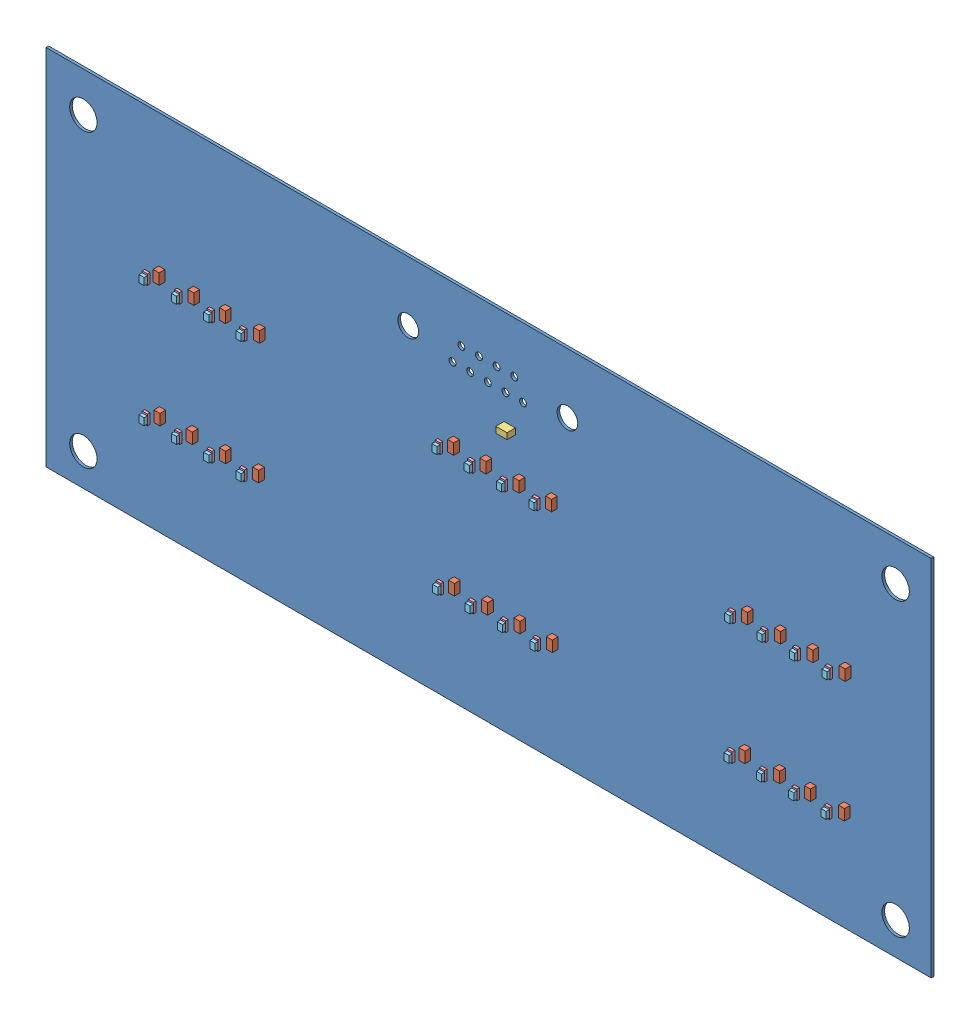
SolidWorks assembly FEV-60_LED_Panel, configuration Default. Lengths in mm.
Overall size (138.94 57.02 1.71).
198 component instances, 5 part files, 0 mates.
Components (placement in the parent):
- FEV-60_LED_Panel.step-1: FEV-60_LED_Panel.step [Default] at origin size (138.94 57.02 1.71)
  - Board.step-1: Board.step [Default] at origin size (138.94 57.02 0.41)
    - Open CASCADE STEP translator 6.8 2.1.1.step-1: Open CASCADE STEP translator 6.8 2.1.1.step [Default] at (0 0 -0.4115) size (138.94 57.02 0.41)
  - R24.step-1: R24.step [Default] at origin size (0.95 1.7 0.9)
    - 6216516608.step-1: 6216516608.step [Default] at (135.509 74.676 0) size (0.95 1.7 0.9)
      - Extruded.step-1: Extruded.step [Default] at origin size (0.95 1.7 0.9)
  - R23.step-1: R23.step [Default] at origin size (0.95 1.7 0.9)
    - 6216516608.step-1: 6216516608.step [Default] at (89.916 74.664 0) size (0.95 1.7 0.9)
      - Extruded.step-1: Extruded.step [Default] at origin size (0.95 1.7 0.9)
  - R22.step-1: R22.step [Default] at origin size (0.95 1.7 0.9)
    - 6216516608.step-1: 6216516608.step [Default] at (43.688 74.676 0) size (0.95 1.7 0.9)
      - Extruded.step-1: Extruded.step [Default] at origin size (0.95 1.7 0.9)
  - R21.step-1: R21.step [Default] at origin size (0.95 1.7 0.9)
    - 6216516608.step-1: 6216516608.step [Default] at (140.97 74.676 0) size (0.95 1.7 0.9)
      - Extruded.step-1: Extruded.step [Default] at origin size (0.95 1.7 0.9)
  - R20.step-1: R20.step [Default] at origin size (0.95 1.7 0.9)
    - 6216516608.step-1: 6216516608.step [Default] at (95.123 74.664 0) size (0.95 1.7 0.9)
      - Extruded.step-1: Extruded.step [Default] at origin size (0.95 1.7 0.9)
  - R19.step-1: R19.step [Default] at origin size (0.95 1.7 0.9)
    - 6216516608.step-1: 6216516608.step [Default] at (48.768 74.676 0) size (0.95 1.7 0.9)
      - Extruded.step-1: Extruded.step [Default] at origin size (0.95 1.7 0.9)
  - R18.step-1: R18.step [Default] at origin size (0.95 1.7 0.9)
    - 6216516608.step-1: 6216516608.step [Default] at (145.796 74.676 0) size (0.95 1.7 0.9)
      - Extruded.step-1: Extruded.step [Default] at origin size (0.95 1.7 0.9)
  - R17.step-1: R17.step [Default] at origin size (0.95 1.7 0.9)
    - 6216516608.step-1: 6216516608.step [Default] at (100.203 74.664 0) size (0.95 1.7 0.9)
      - Extruded.step-1: Extruded.step [Default] at origin size (0.95 1.7 0.9)
  - R16.step-1: R16.step [Default] at origin size (0.95 1.7 0.9)
    - 6216516608.step-1: 6216516608.step [Default] at (53.975 74.676 0) size (0.95 1.7 0.9)
      - Extruded.step-1: Extruded.step [Default] at origin size (0.95 1.7 0.9)
  - R15.step-1: R15.step [Default] at origin size (0.95 1.7 0.9)
    - 6216516608.step-1: 6216516608.step [Default] at (151.13 74.688 0) size (0.95 1.7 0.9)
      - Extruded.step-1: Extruded.step [Default] at origin size (0.95 1.7 0.9)
  - R14.step-1: R14.step [Default] at origin size (0.95 1.7 0.9)
    - 6216516608.step-1: 6216516608.step [Default] at (105.283 74.664 0) size (0.95 1.7 0.9)
      - Extruded.step-1: Extruded.step [Default] at origin size (0.95 1.7 0.9)
  - R13.step-1: R13.step [Default] at origin size (0.95 1.7 0.9)
    - 6216516608.step-1: 6216516608.step [Default] at (59.182 74.676 0) size (0.95 1.7 0.9)
      - Extruded.step-1: Extruded.step [Default] at origin size (0.95 1.7 0.9)
  - R12.step-1: R12.step [Default] at origin size (0.95 1.7 0.9)
    - 6216516608.step-1: 6216516608.step [Default] at (135.89 93.726 0) size (0.95 1.7 0.9)
      - Extruded.step-1: Extruded.step [Default] at origin size (0.95 1.7 0.9)
  - R11.step-1: R11.step [Default] at origin size (0.95 1.7 0.9)
    - 6216516608.step-1: 6216516608.step [Default] at (89.789 93.726 0) size (0.95 1.7 0.9)
      - Extruded.step-1: Extruded.step [Default] at origin size (0.95 1.7 0.9)
  - R10.step-1: R10.step [Default] at origin size (0.95 1.7 0.9)
    - 6216516608.step-1: 6216516608.step [Default] at (43.561 93.726 0) size (0.95 1.7 0.9)
      - Extruded.step-1: Extruded.step [Default] at origin size (0.95 1.7 0.9)
  - R9.step-1: R9.step [Default] at origin size (0.95 1.7 0.9)
    - 6216516608.step-1: 6216516608.step [Default] at (141.097 93.726 0) size (0.95 1.7 0.9)
      - Extruded.step-1: Extruded.step [Default] at origin size (0.95 1.7 0.9)
  - R8.step-1: R8.step [Default] at origin size (0.95 1.7 0.9)
    - 6216516608.step-1: 6216516608.step [Default] at (94.869 93.726 0) size (0.95 1.7 0.9)
      - Extruded.step-1: Extruded.step [Default] at origin size (0.95 1.7 0.9)
  - R7.step-1: R7.step [Default] at origin size (0.95 1.7 0.9)
    - 6216516608.step-1: 6216516608.step [Default] at (49.022 93.726 0) size (0.95 1.7 0.9)
      - Extruded.step-1: Extruded.step [Default] at origin size (0.95 1.7 0.9)
  - R6.step-1: R6.step [Default] at origin size (0.95 1.7 0.9)
    - 6216516608.step-1: 6216516608.step [Default] at (146.177 93.726 0) size (0.95 1.7 0.9)
      - Extruded.step-1: Extruded.step [Default] at origin size (0.95 1.7 0.9)
  - R5.step-1: R5.step [Default] at origin size (0.95 1.7 0.9)
    - 6216516608.step-1: 6216516608.step [Default] at (100.076 93.726 0) size (0.95 1.7 0.9)
      - Extruded.step-1: Extruded.step [Default] at origin size (0.95 1.7 0.9)
  - R4.step-1: R4.step [Default] at origin size (0.95 1.7 0.9)
    - 6216516608.step-1: 6216516608.step [Default] at (53.975 93.726 0) size (0.95 1.7 0.9)
      - Extruded.step-1: Extruded.step [Default] at origin size (0.95 1.7 0.9)
  - R3.step-1: R3.step [Default] at origin size (0.95 1.7 0.9)
    - 6216516608.step-1: 6216516608.step [Default] at (151.257 93.726 0) size (0.95 1.7 0.9)
      - Extruded.step-1: Extruded.step [Default] at origin size (0.95 1.7 0.9)
  - R2.step-1: R2.step [Default] at origin size (0.95 1.7 0.9)
    - 6216516608.step-1: 6216516608.step [Default] at (105.156 93.726 0) size (0.95 1.7 0.9)
      - Extruded.step-1: Extruded.step [Default] at origin size (0.95 1.7 0.9)
  - C1.step-1: C1.step [Default] at origin size (1.75 0.95 1.3)
    - 6216520128.step-1: 6216520128.step [Default] at (98.171 100.076 0) size (1.75 0.95 1.3)
      - Extruded-0.step-1: Extruded-0.step [Default] at origin size (1.75 0.95 1.3)
  - R1.step-1: R1.step [Default] at origin size (0.95 1.7 0.9)
    - 6216516608.step-1: 6216516608.step [Default] at (59.309 93.726 0) size (0.95 1.7 0.9)
      - Extruded.step-1: Extruded.step [Default] at origin size (0.95 1.7 0.9)
  - DS24.step-1: DS24.step [Default] at origin size (0.8 1.6 0.9)
    - 6363329008.step-1: 6363329008.step [Default] at (133.0958 73.1522 0) size (0.8 1.6 0.4)
      - Extruded-1.step-1: Extruded-1.step [Default] at origin size (0.8 1.6 0.4)
    - 6363328768.step-1: 6363328768.step [Default] at (133.0958 73.1522 0.4) size (0.8 1.1 0.5)
      - Extruded-2.step-1: Extruded-2.step [Default] at origin size (0.8 1.1 0.5)
  - DS23.step-1: DS23.step [Default] at origin size (0.8 1.6 0.9)
    - 6363329008.step-1: 6363329008.step [Default] at (87.3759 73.1521 0) size (0.8 1.6 0.4)
      - Extruded-1.step-1: Extruded-1.step [Default] at origin size (0.8 1.6 0.4)
    - 6363328768.step-1: 6363328768.step [Default] at (87.3759 73.1521 0.4) size (0.8 1.1 0.5)
      - Extruded-2.step-1: Extruded-2.step [Default] at origin size (0.8 1.1 0.5)
  - DS22.step-1: DS22.step [Default] at origin size (0.8 1.6 0.9)
    - 6363329008.step-1: 6363329008.step [Default] at (41.2749 73.1521 0) size (0.8 1.6 0.4)
      - Extruded-1.step-1: Extruded-1.step [Default] at origin size (0.8 1.6 0.4)
    - 6363328768.step-1: 6363328768.step [Default] at (41.2749 73.1521 0.4) size (0.8 1.1 0.5)
      - Extruded-2.step-1: Extruded-2.step [Default] at origin size (0.8 1.1 0.5)
  - DS21.step-1: DS21.step [Default] at origin size (0.8 1.6 0.9)
    - 6363329008.step-1: 6363329008.step [Default] at (138.1758 73.1522 0) size (0.8 1.6 0.4)
      - Extruded-1.step-1: Extruded-1.step [Default] at origin size (0.8 1.6 0.4)
    - 6363328768.step-1: 6363328768.step [Default] at (138.1758 73.1522 0.4) size (0.8 1.1 0.5)
      - Extruded-2.step-1: Extruded-2.step [Default] at origin size (0.8 1.1 0.5)
  - DS20.step-1: DS20.step [Default] at origin size (0.8 1.6 0.9)
    - 6363329008.step-1: 6363329008.step [Default] at (92.4559 73.1521 0) size (0.8 1.6 0.4)
      - Extruded-1.step-1: Extruded-1.step [Default] at origin size (0.8 1.6 0.4)
    - 6363328768.step-1: 6363328768.step [Default] at (92.4559 73.1521 0.4) size (0.8 1.1 0.5)
      - Extruded-2.step-1: Extruded-2.step [Default] at origin size (0.8 1.1 0.5)
  - DS19.step-1: DS19.step [Default] at origin size (0.8 1.6 0.9)
    - 6363329008.step-1: 6363329008.step [Default] at (46.3549 73.1521 0) size (0.8 1.6 0.4)
      - Extruded-1.step-1: Extruded-1.step [Default] at origin size (0.8 1.6 0.4)
    - 6363328768.step-1: 6363328768.step [Default] at (46.3549 73.1521 0.4) size (0.8 1.1 0.5)
      - Extruded-2.step-1: Extruded-2.step [Default] at origin size (0.8 1.1 0.5)
  - DS18.step-1: DS18.step [Default] at origin size (0.8 1.6 0.9)
    - 6363329008.step-1: 6363329008.step [Default] at (143.2558 73.1522 0) size (0.8 1.6 0.4)
      - Extruded-1.step-1: Extruded-1.step [Default] at origin size (0.8 1.6 0.4)
    - 6363328768.step-1: 6363328768.step [Default] at (143.2558 73.1522 0.4) size (0.8 1.1 0.5)
      - Extruded-2.step-1: Extruded-2.step [Default] at origin size (0.8 1.1 0.5)
  - DS17.step-1: DS17.step [Default] at origin size (0.8 1.6 0.9)
    - 6363329008.step-1: 6363329008.step [Default] at (97.5359 73.1521 0) size (0.8 1.6 0.4)
      - Extruded-1.step-1: Extruded-1.step [Default] at origin size (0.8 1.6 0.4)
    - 6363328768.step-1: 6363328768.step [Default] at (97.5359 73.1521 0.4) size (0.8 1.1 0.5)
      - Extruded-2.step-1: Extruded-2.step [Default] at origin size (0.8 1.1 0.5)
  - DS16.step-1: DS16.step [Default] at origin size (0.8 1.6 0.9)
    - 6363329008.step-1: 6363329008.step [Default] at (51.4349 73.1521 0) size (0.8 1.6 0.4)
      - Extruded-1.step-1: Extruded-1.step [Default] at origin size (0.8 1.6 0.4)
    - 6363328768.step-1: 6363328768.step [Default] at (51.4349 73.1521 0.4) size (0.8 1.1 0.5)
      - Extruded-2.step-1: Extruded-2.step [Default] at origin size (0.8 1.1 0.5)
  - DS15.step-1: DS15.step [Default] at origin size (0.8 1.6 0.9)
    - 6363329008.step-1: 6363329008.step [Default] at (148.3358 73.1522 0) size (0.8 1.6 0.4)
      - Extruded-1.step-1: Extruded-1.step [Default] at origin size (0.8 1.6 0.4)
    - 6363328768.step-1: 6363328768.step [Default] at (148.3358 73.1522 0.4) size (0.8 1.1 0.5)
      - Extruded-2.step-1: Extruded-2.step [Default] at origin size (0.8 1.1 0.5)
  - DS14.step-1: DS14.step [Default] at origin size (0.8 1.6 0.9)
    - 6363329008.step-1: 6363329008.step [Default] at (102.6159 73.1521 0) size (0.8 1.6 0.4)
      - Extruded-1.step-1: Extruded-1.step [Default] at origin size (0.8 1.6 0.4)
    - 6363328768.step-1: 6363328768.step [Default] at (102.6159 73.1521 0.4) size (0.8 1.1 0.5)
      - Extruded-2.step-1: Extruded-2.step [Default] at origin size (0.8 1.1 0.5)
  - DS13.step-1: DS13.step [Default] at origin size (0.8 1.6 0.9)
    - 6363329008.step-1: 6363329008.step [Default] at (56.5149 73.1521 0) size (0.8 1.6 0.4)
      - Extruded-1.step-1: Extruded-1.step [Default] at origin size (0.8 1.6 0.4)
    - 6363328768.step-1: 6363328768.step [Default] at (56.5149 73.1521 0.4) size (0.8 1.1 0.5)
      - Extruded-2.step-1: Extruded-2.step [Default] at origin size (0.8 1.1 0.5)
  - DS12.step-1: DS12.step [Default] at origin size (0.8 1.6 0.9)
    - 6363329008.step-1: 6363329008.step [Default] at (133.2228 92.2022 0) size (0.8 1.6 0.4)
      - Extruded-1.step-1: Extruded-1.step [Default] at origin size (0.8 1.6 0.4)
    - 6363328768.step-1: 6363328768.step [Default] at (133.2228 92.2022 0.4) size (0.8 1.1 0.5)
      - Extruded-2.step-1: Extruded-2.step [Default] at origin size (0.8 1.1 0.5)
  - DS11.step-1: DS11.step [Default] at origin size (0.8 1.6 0.9)
    - 6363329008.step-1: 6363329008.step [Default] at (87.249 92.214 0) size (0.8 1.6 0.4)
      - Extruded-1.step-1: Extruded-1.step [Default] at origin size (0.8 1.6 0.4)
    - 6363328768.step-1: 6363328768.step [Default] at (87.249 92.214 0.4) size (0.8 1.1 0.5)
      - Extruded-2.step-1: Extruded-2.step [Default] at origin size (0.8 1.1 0.5)
  - DS10.step-1: DS10.step [Default] at origin size (0.8 1.6 0.9)
    - 6363329008.step-1: 6363329008.step [Default] at (41.275 92.214 0) size (0.8 1.6 0.4)
      - Extruded-1.step-1: Extruded-1.step [Default] at origin size (0.8 1.6 0.4)
    - 6363328768.step-1: 6363328768.step [Default] at (41.275 92.214 0.4) size (0.8 1.1 0.5)
      - Extruded-2.step-1: Extruded-2.step [Default] at origin size (0.8 1.1 0.5)
  - DS9.step-1: DS9.step [Default] at origin size (0.8 1.6 0.9)
    - 6363329008.step-1: 6363329008.step [Default] at (138.3028 92.2022 0) size (0.8 1.6 0.4)
      - Extruded-1.step-1: Extruded-1.step [Default] at origin size (0.8 1.6 0.4)
    - 6363328768.step-1: 6363328768.step [Default] at (138.3028 92.2022 0.4) size (0.8 1.1 0.5)
      - Extruded-2.step-1: Extruded-2.step [Default] at origin size (0.8 1.1 0.5)
  - DS8.step-1: DS8.step [Default] at origin size (0.8 1.6 0.9)
    - 6363329008.step-1: 6363329008.step [Default] at (92.3289 92.2021 0) size (0.8 1.6 0.4)
      - Extruded-1.step-1: Extruded-1.step [Default] at origin size (0.8 1.6 0.4)
    - 6363328768.step-1: 6363328768.step [Default] at (92.3289 92.2021 0.4) size (0.8 1.1 0.5)
      - Extruded-2.step-1: Extruded-2.step [Default] at origin size (0.8 1.1 0.5)
  - DS7.step-1: DS7.step [Default] at origin size (0.8 1.6 0.9)
    - 6363329008.step-1: 6363329008.step [Default] at (46.3549 92.2021 0) size (0.8 1.6 0.4)
      - Extruded-1.step-1: Extruded-1.step [Default] at origin size (0.8 1.6 0.4)
    - 6363328768.step-1: 6363328768.step [Default] at (46.3549 92.2021 0.4) size (0.8 1.1 0.5)
      - Extruded-2.step-1: Extruded-2.step [Default] at origin size (0.8 1.1 0.5)
  - DS6.step-1: DS6.step [Default] at origin size (0.8 1.6 0.9)
    - 6363329008.step-1: 6363329008.step [Default] at (143.3828 92.2022 0) size (0.8 1.6 0.4)
      - Extruded-1.step-1: Extruded-1.step [Default] at origin size (0.8 1.6 0.4)
    - 6363328768.step-1: 6363328768.step [Default] at (143.3828 92.2022 0.4) size (0.8 1.1 0.5)
      - Extruded-2.step-1: Extruded-2.step [Default] at origin size (0.8 1.1 0.5)
  - DS5.step-1: DS5.step [Default] at origin size (0.8 1.6 0.9)
    - 6363329008.step-1: 6363329008.step [Default] at (97.4089 92.2021 0) size (0.8 1.6 0.4)
      - Extruded-1.step-1: Extruded-1.step [Default] at origin size (0.8 1.6 0.4)
    - 6363328768.step-1: 6363328768.step [Default] at (97.4089 92.2021 0.4) size (0.8 1.1 0.5)
      - Extruded-2.step-1: Extruded-2.step [Default] at origin size (0.8 1.1 0.5)
  - DS4.step-1: DS4.step [Default] at origin size (0.8 1.6 0.9)
    - 6363329008.step-1: 6363329008.step [Default] at (51.4349 92.2021 0) size (0.8 1.6 0.4)
      - Extruded-1.step-1: Extruded-1.step [Default] at origin size (0.8 1.6 0.4)
    - 6363328768.step-1: 6363328768.step [Default] at (51.4349 92.2021 0.4) size (0.8 1.1 0.5)
      - Extruded-2.step-1: Extruded-2.step [Default] at origin size (0.8 1.1 0.5)
  - DS3.step-1: DS3.step [Default] at origin size (0.8 1.6 0.9)
    - 6363329008.step-1: 6363329008.step [Default] at (148.4628 92.2022 0) size (0.8 1.6 0.4)
      - Extruded-1.step-1: Extruded-1.step [Default] at origin size (0.8 1.6 0.4)
    - 6363328768.step-1: 6363328768.step [Default] at (148.4628 92.2022 0.4) size (0.8 1.1 0.5)
      - Extruded-2.step-1: Extruded-2.step [Default] at origin size (0.8 1.1 0.5)
  - DS2.step-1: DS2.step [Default] at origin size (0.8 1.6 0.9)
    - 6363329008.step-1: 6363329008.step [Default] at (102.4889 92.2021 0) size (0.8 1.6 0.4)
      - Extruded-1.step-1: Extruded-1.step [Default] at origin size (0.8 1.6 0.4)
    - 6363328768.step-1: 6363328768.step [Default] at (102.4889 92.2021 0.4) size (0.8 1.1 0.5)
      - Extruded-2.step-1: Extruded-2.step [Default] at origin size (0.8 1.1 0.5)
  - DS1.step-1: DS1.step [Default] at origin size (0.8 1.6 0.9)
    - 6363329008.step-1: 6363329008.step [Default] at (56.5149 92.2021 0) size (0.8 1.6 0.4)
      - Extruded-1.step-1: Extruded-1.step [Default] at origin size (0.8 1.6 0.4)
    - 6363328768.step-1: 6363328768.step [Default] at (56.5149 92.2021 0.4) size (0.8 1.1 0.5)
      - Extruded-2.step-1: Extruded-2.step [Default] at origin size (0.8 1.1 0.5)
